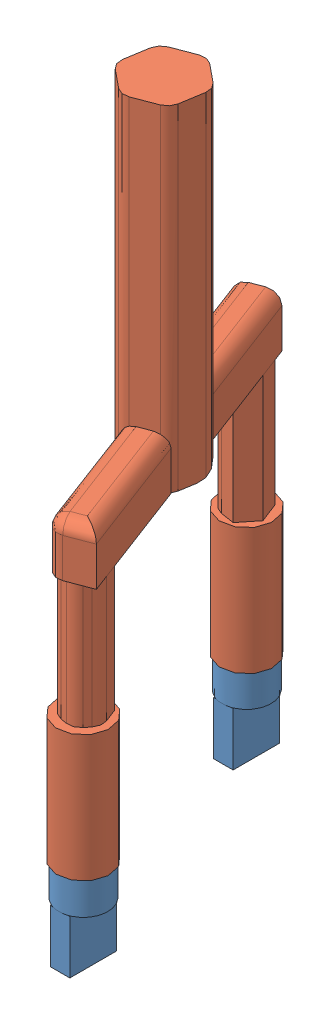
SolidWorks assembly Сборка1, configuration По умолчанию. Lengths in mm.
Overall size (280.65 533.28 266.09).
3 component instances, 2 part files, 2 mates.
Components (placement in the parent):
- 2-1: 2 [По умолчанию] at (-96.3733 47.5146 58.4908) size (38.64 84 38.64)
- Деталь2-1: Деталь2 [По умолчанию] at (-135.4337 538.7985 -44.3753) x (-0.837169 0 -0.546944) z (-0.546944 0 0.837169) size (222.59 465.37 172.42)
- 2-2: 2 [По умолчанию] at (-173.6093 48.0888 -147.7532) size (38.64 84 38.64)
Mates (geometry in assembly coordinates):
- Концентричный2: concentric aligned: cylinder of 2-1 through (-96.3733 89.5146 58.4908) axis (0 -1 0) radius 19.32; cylinder of Деталь2-1 through (-96.3733 168.4321 58.4908) axis (0 -1 0) radius 19.32
- Концентричный3: concentric aligned: cylinder of Деталь2-1 through (-173.6093 168.4321 -147.7532) axis (0 -1 0) radius 19.32; cylinder of 2-2 through (-173.6093 90.0888 -147.7532) axis (0 -1 0) radius 19.32
